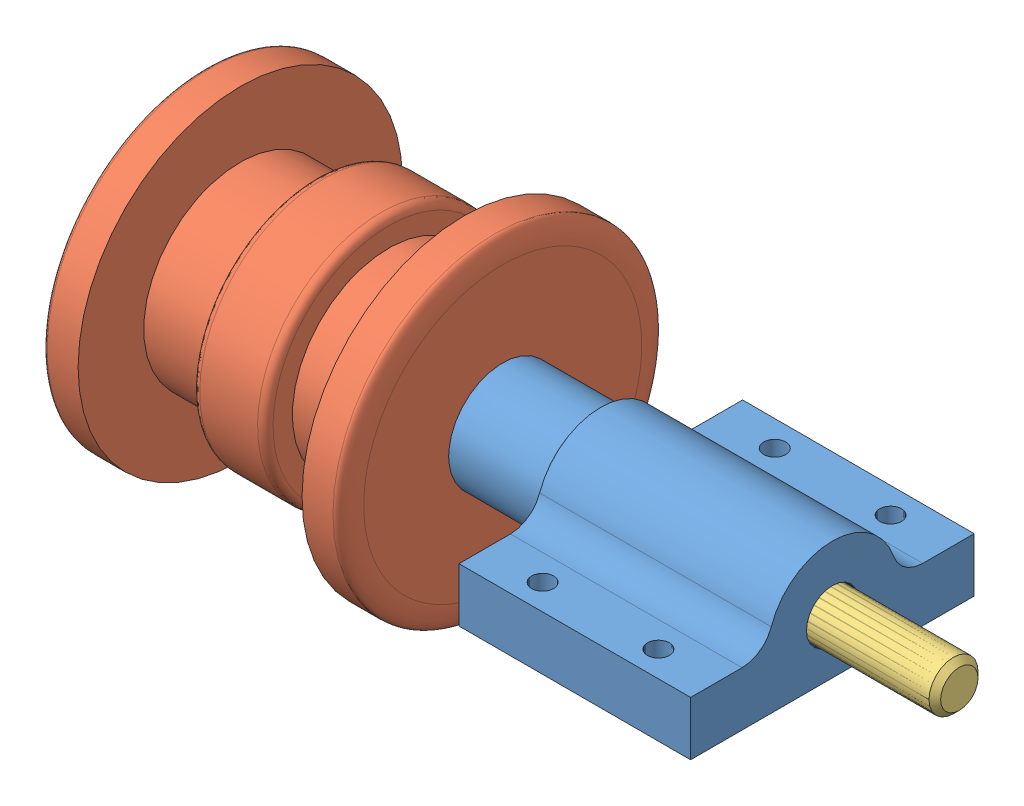
SolidWorks assembly Pillow_Block_Assem, configuration Default. Lengths in mm.
Overall size (98.15 55.95 55.95).
4 component instances, 4 part files, 6 mates.
Components (placement in the parent):
- Pillow Block 0.25in-1: Pillow Block 0.25in [Default] at origin size (42.7 15.37 36.73)
- Idler_0.25in_Mount-1: Idler_0.25in_Mount [Default] at (-12.7 0 0) x (-1 0 0) z (0 -0.924225 -0.381849) size (39.03 42.84 42.84)
- socket head cap screw_ai-1: socket head cap screw_ai [HX-SHCS 0.25-20x3.5x1-C] at (-48.812 0 0) size (95.25 9.53 9.53)
- Washer-1: Washer [Default] at (-42.462 0 0) x (0 -1 0) z (0 0 1) size (19.05 0.76 19.05)
Mates (geometry in assembly coordinates):
- Concentric1: concentric anti-aligned: circle of socket head cap screw_ai-1; circle of Washer-1
- Concentric2: concentric aligned: circle of Idler_0.25in_Mount-1; circle of socket head cap screw_ai-1
- Coincident1: coincident anti-aligned: plane of socket head cap screw_ai-1 through (-42.462 4.7625 0) normal (1 0 0); plane of Washer-1 through (-42.462 0 0) normal (-1 0 0)
- Coincident2: coincident anti-aligned: plane of Idler_0.25in_Mount-1 through (-41.7 0 0) normal (-1 0 0); plane of Washer-1 through (-41.7 0 0) normal (1 0 0)
- Concentric3: concentric aligned: circle of Pillow Block 0.25in-1; circle of socket head cap screw_ai-1
- Coincident3: coincident anti-aligned: plane of Pillow Block 0.25in-1 through (-12.7 0 0) normal (-1 0 0); plane of Idler_0.25in_Mount-1 through (-12.7 0 0) normal (1 0 0)
